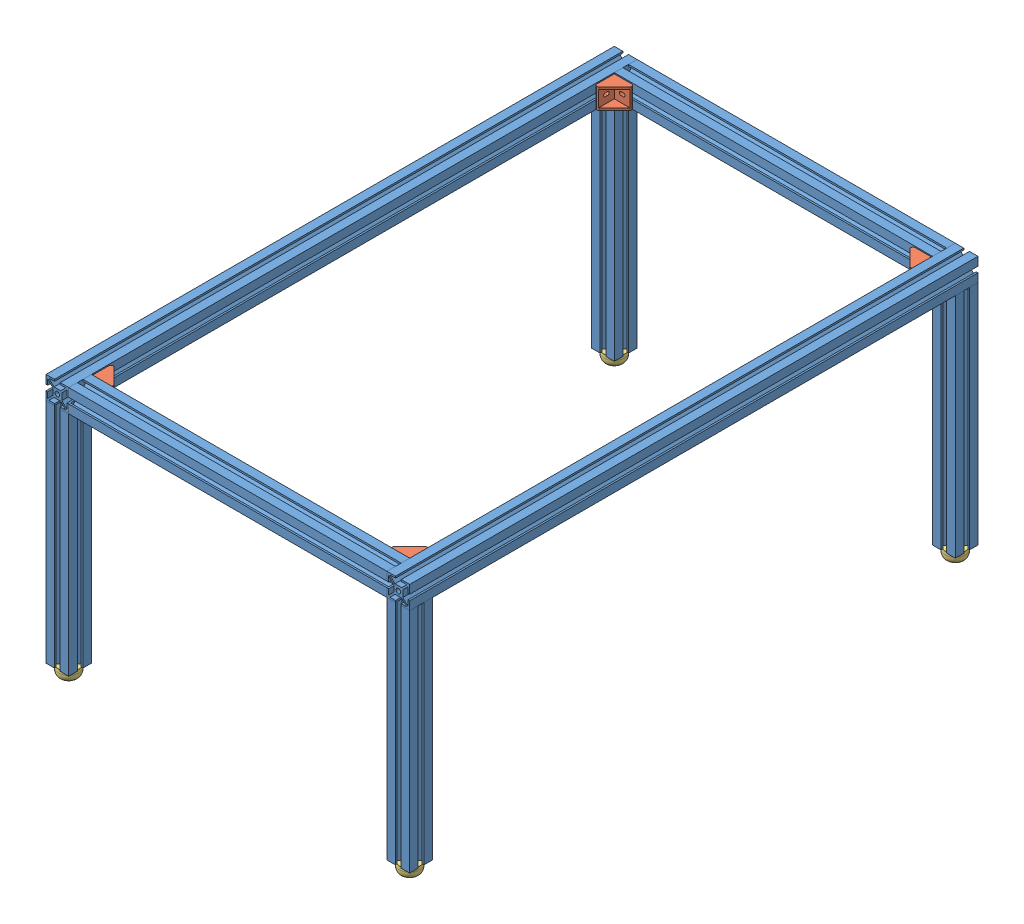
SolidWorks assembly Stolik, configuration Domyślna. Lengths in mm.
Overall size (324.76 230.04 503.39).
16 component instances, 3 part files, 46 mates.
Components (placement in the parent):
- Profil20-1: Profil20 [200] at (150 10 240) x (0 0 -1) z (1 0 0) size (20 200 20)
- Profil20-2: Profil20 [200] at (-150 10 240) x (0 0 -1) z (1 0 0) size (20 200 20)
- Profil20-3: Profil20 [200] at (-150 10 -240) x (0 0 -1) z (1 0 0) size (20 200 20)
- Profil20-4: Profil20 [200] at (150 10 -240) size (20 200 20)
- Lacznik-1: Lacznik [Domyślna] at (140 211 230) size (17.17 18 17.17)
- Lacznik-2: Lacznik [Domyślna] at (140 211 -230) x (0 0 -1) z (1 0 0) size (17.17 18 17.17)
- Lacznik-3: Lacznik [Domyślna] at (-140 229 230) x (-1 0 0) z (0 0 1) size (17.17 18 17.17)
- Lacznik-4: Lacznik [Domyślna] at (-140 229 -230) x (0 0 -1) z (-1 0 0) size (17.17 18 17.17)
- Profil20-5: Profil20 [280] at (-140 220 -240) x (0 0 1) z (0 1 0) size (20 280 20)
- Profil20-6: Profil20 [280] at (-140 220 240) x (0 0 1) z (0 1 0) size (20 280 20)
- Profil20-7: Profil20 [500] at (-150 220 250) x (-1 0 0) z (0 -1 0) size (20 500 20)
- Profil20-8: Profil20 [500] at (150 220 -250) x (0 -1 0) z (-1 0 0) size (20 500 20)
- stopka-1: stopka [Domyślna] at (150 10 240) x (-0.837169 0 -0.546944) z (-0.546944 0 0.837169) size (18.42 10.04 18.42)
- stopka-2: stopka [Domyślna] at (-150 10 240) x (-0.925243 0 -0.379375) z (-0.379375 0 0.925243) size (18.42 10.04 18.42)
- stopka-4: stopka [Domyślna] at (-150 10 -240) x (-0.985271 0 -0.170998) z (-0.170998 0 0.985271) size (18.42 10.04 18.42)
- stopka-6: stopka [Domyślna] at (150 10 -240) x (-0.997902 0 0.064746) z (0.064746 0 0.997902) size (18.42 10.04 18.42)
Mates (geometry in assembly coordinates):
- Wspólnie4: coincident anti-aligned: plane of Lacznik-2 through (140 219 -230) normal (0 0 -1); plane of Profil20-5 through (140 210 -230) normal (0 0 1)
- Wspólnie5: coincident aligned: plane of Lacznik-2 through (140 219 -230) normal (1 0 0); plane of Profil20-5 through (140 210 -240) normal (1 0 0)
- Szerokość1: width anti-aligned: plane of Lacznik-2 through (140 219 -230) normal (0 1 0); plane of Lacznik-2 through (140 201 -230) normal (0 -1 0); plane of Profil20-5 through (140 200 -240) normal (0 -1 0); plane of Profil20-5 through (140 220 -240) normal (0 1 0)
- Wspólnie6: coincident anti-aligned: plane of Lacznik-2 through (140 219 -230) normal (1 0 0); plane of Profil20-8 through (140 210 250) normal (-1 0 0)
- Wspólnie7: coincident aligned: plane of Profil20-5 through (140 210 -250) normal (0 0 -1); plane of Profil20-8 through (150 210 -250) normal (0 0 -1)
- Wspólnie8: coincident aligned: plane of Profil20-5 through (140 220 -240) normal (0 1 0); plane of Profil20-8 through (150 220 250) normal (0 1 0)
- Wspólnie9: coincident aligned: plane of Profil20-5 through (140 210 -250) normal (0 0 -1); plane of Profil20-7 through (-150 210 -250) normal (0 0 -1)
- Wspólnie10: coincident aligned: plane of Profil20-5 through (140 220 -240) normal (0 1 0); plane of Profil20-7 through (-150 220 -250) normal (0 1 0)
- Wspólnie11: coincident anti-aligned: plane of Profil20-6 through (140 210 240) normal (1 0 0); plane of Profil20-8 through (140 210 250) normal (-1 0 0)
- Wspólnie13: coincident aligned: plane of Profil20-6 through (140 220 240) normal (0 1 0); plane of Profil20-8 through (150 220 250) normal (0 1 0)
- Szerokość2: width aligned: plane of Lacznik-1 through (140 219 230) normal (0 1 0); plane of Lacznik-1 through (140 201 230) normal (0 -1 0); plane of Profil20-8 through (150 220 250) normal (0 1 0); plane of Profil20-8 through (150 200 250) normal (0 -1 0)
- Wspólnie14: coincident anti-aligned: plane of Lacznik-1 through (140 219 230) normal (1 0 0); plane of Profil20-8 through (140 210 250) normal (-1 0 0)
- Wspólnie15: coincident anti-aligned: plane of Lacznik-1 through (140 219 230) normal (0 0 1); plane of Profil20-6 through (140 210 230) normal (0 0 -1)
- Wspólnie16: coincident anti-aligned: plane of Lacznik-3 through (-140 201 230) normal (0 0 1); plane of Profil20-6 through (140 210 230) normal (0 0 -1)
- Wspólnie17: coincident anti-aligned: plane of Lacznik-3 through (-140 201 230) normal (-1 0 0); plane of Profil20-7 through (-140 210 -250) normal (1 0 0)
- Wspólnie18: coincident anti-aligned: plane of Profil20-6 through (-140 210 240) normal (-1 0 0); plane of Profil20-7 through (-140 210 -250) normal (1 0 0)
- Wspólnie19: coincident anti-aligned: plane of Lacznik-4 through (-140 201 -230) normal (0 0 -1); plane of Profil20-5 through (140 210 -230) normal (0 0 1)
- Wspólnie20: coincident anti-aligned: plane of Lacznik-4 through (-140 201 -230) normal (-1 0 0); plane of Profil20-7 through (-140 210 -250) normal (1 0 0)
- Szerokość3: width anti-aligned: plane of Profil20-7 through (-150 220 -250) normal (0 1 0); plane of Profil20-7 through (-150 200 -250) normal (0 -1 0); plane of Lacznik-4 through (-140 201 -230) normal (0 -1 0); plane of Lacznik-4 through (-140 219 -230) normal (0 1 0)
- Szerokość4: width anti-aligned: plane of Lacznik-3 through (-140 219 230) normal (0 1 0); plane of Lacznik-3 through (-140 201 230) normal (0 -1 0); plane of Profil20-7 through (-150 200 -250) normal (0 -1 0); plane of Profil20-7 through (-150 220 -250) normal (0 1 0)
- Wspólnie21: coincident aligned: plane of Profil20-6 through (140 210 250) normal (0 0 1); plane of Profil20-7 through (-150 210 250) normal (0 0 1)
- Wspólnie22: coincident anti-aligned: plane of Profil20-1 through (150 200 240) normal (0 1 0); plane of Profil20-8 through (150 200 250) normal (0 -1 0)
- Wspólnie23: coincident aligned: plane of Profil20-1 through (160 200 240) normal (1 0 0); plane of Profil20-8 through (160 210 250) normal (1 0 0)
- Wspólnie24: coincident aligned: plane of Profil20-1 through (150 200 250) normal (0 0 1); plane of Profil20-6 through (140 210 250) normal (0 0 1)
- Wspólnie25: coincident aligned: plane of Profil20-4 through (160 200 -240) normal (1 0 0); plane of Profil20-8 through (160 210 250) normal (1 0 0)
- Wspólnie26: coincident aligned: plane of Profil20-4 through (150 200 -250) normal (0 0 -1); plane of Profil20-5 through (140 210 -250) normal (0 0 -1)
- Wspólnie27: coincident anti-aligned: plane of Profil20-4 through (150 200 -240) normal (0 1 0); plane of Profil20-8 through (150 200 250) normal (0 -1 0)
- Wspólnie28: coincident aligned: plane of Profil20-3 through (-150 200 -250) normal (0 0 -1); plane of Profil20-5 through (140 210 -250) normal (0 0 -1)
- Wspólnie29: coincident aligned: plane of Profil20-3 through (-160 200 -240) normal (-1 0 0); plane of Profil20-7 through (-160 210 -250) normal (-1 0 0)
- Wspólnie30: coincident anti-aligned: plane of Profil20-3 through (-150 200 -240) normal (0 1 0); plane of Profil20-7 through (-150 200 -250) normal (0 -1 0)
- Wspólnie31: coincident aligned: plane of Profil20-2 through (-160 200 240) normal (-1 0 0); plane of Profil20-7 through (-160 210 -250) normal (-1 0 0)
- Wspólnie32: coincident aligned: plane of Profil20-2 through (-150 200 250) normal (0 0 1); plane of Profil20-6 through (140 210 250) normal (0 0 1)
- Wspólnie33: coincident anti-aligned: plane of Profil20-2 through (-150 200 240) normal (0 1 0); plane of Profil20-7 through (-150 200 -250) normal (0 -1 0)
- Równolegle1: parallel aligned: plane of Profil20-4 through (150 0 -240) normal (0 0 1); plane of assembly through (0 0 0) normal (0 0 1)
- Równolegle2: parallel aligned: plane of Profil20-4 through (150 0 -240) normal (1 0 0); plane of assembly through (0 0 0) normal (1 0 0)
- Wspólnie35: coincident anti-aligned: plane of stopka-1 through (150 0 240) normal (0 -1 0); plane of assembly
- Symetrycznie1: symmetric aligned: plane of Profil20-5 through (140 210 -250) normal (0 0 -1); plane of Profil20-6 through (140 210 250) normal (0 0 1); plane of assembly through (0 0 0) normal (0 0 1)
- Symetrycznie2: symmetric aligned: plane of Profil20-7 through (-160 210 -250) normal (-1 0 0); plane of Profil20-8 through (160 210 250) normal (1 0 0); plane of assembly through (0 0 0) normal (1 0 0)
- Wspólnie41: coincident anti-aligned: plane of Profil20-1 through (150 0 240) normal (0 -1 0); plane of stopka-1 through (159.1889 -0.607 254.6311) normal (0 1 0)
- Koncentryczne1: concentric anti-aligned: cylinder of Profil20-1 through (150 200 240) axis (0 -1 0) radius 2; cylinder of stopka-1 through (159.1889 -10.643 254.6311) axis (0 1 0) radius 1.5
- Wspólnie42: coincident anti-aligned: plane of Profil20-2 through (-150 0 240) normal (0 -1 0); plane of stopka-2 through (-150 0 240) normal (0 1 0)
- Koncentryczne2: concentric anti-aligned: cylinder of Profil20-2 through (-150 200 240) axis (0 -1 0) radius 2; cylinder of stopka-2 through (-150 -10.036 240) axis (0 1 0) radius 1.5
- Wspólnie43: coincident anti-aligned: plane of Profil20-3 through (-150 0 -240) normal (0 -1 0); plane of stopka-4 through (-150 0 -240) normal (0 1 0)
- Koncentryczne3: concentric anti-aligned: cylinder of Profil20-3 through (-150 200 -240) axis (0 -1 0) radius 2; cylinder of stopka-4 through (-150 -10.036 -240) axis (0 1 0) radius 1.5
- Wspólnie44: coincident anti-aligned: plane of Profil20-4 through (150 0 -240) normal (0 -1 0); plane of stopka-6 through (150 0 -240) normal (0 1 0)
- Koncentryczne4: concentric anti-aligned: cylinder of Profil20-4 through (150 200 -240) axis (0 -1 0) radius 2; cylinder of stopka-6 through (150 -10.036 -240) axis (0 1 0) radius 1.5
